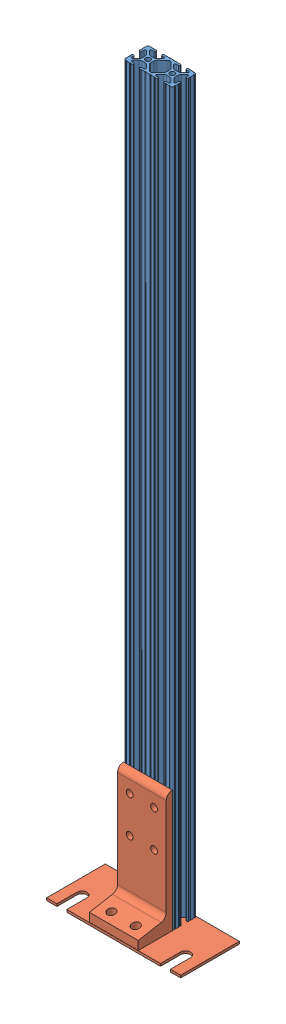
SolidWorks assembly 2010 support assembley, configuration Default. Lengths in mm.
Overall size (139.7 763.52 61.15).
3 component instances, 2 part files, 6 mates.
Components (placement in the parent):
- 8020-1020 29-96in-1: 8020-1020 29-96in [Default] at (16.9292 0 -12.7) x (1 0 0) z (0 -1 0) size (50.8 25.4 760.98)
- 8020-2385-CUT-1: 8020-2385-CUT [Default] at (17.1581 -6.8903 -18.4355) x (0 0 -1) z (1 0 0) (suppressed, hidden)
- 8020-2385-MODIFIED-1: 8020-2385-MODIFIED [Default] at (17.1581 -6.8903 -20.5691) x (0 0 -1) z (1 0 0) size (61.15 129.54 139.7)
Mates (geometry in assembly coordinates):
- Coincident1: coincident anti-aligned: plane of 8020-1020 29-96in-1 through (33.9167 0 -1.049) normal (0 -1 0); plane of assembly through (0 0 0) normal (0 1 0)
- Coincident3: coincident anti-aligned: plane of 8020-1020 29-96in-1 through (33.9167 0 -1.049) normal (0 -1 0); plane of ? through (16.9292 0 142.1782) normal (0 1 0)
- Coincident4: coincident anti-aligned: plane of 8020-1020 29-96in-1 through (14.7956 760.984 -25.4) normal (0 0 -1); plane of ? through (42.3292 -72.7717 -25.4) normal (0 0 1)
- Coincident5: coincident: plane of 8020-1020 29-96in-1 through (19.0628 760.984 0) normal (0 0 1); plane of 8020-2385-MODIFIED-1 through (-8.4708 -72.7717 0) normal (0 0 -1)
- Coincident6: coincident: plane of 8020-1020 29-96in-1 through (33.9167 0 -1.049) normal (0 -1 0); plane of 8020-2385-MODIFIED-1 through (16.9292 0 140.0446) normal (0 1 0)
- Coincident7: coincident: moEndPointRef_w of 8020-1020 29-96in-1; moEndPointRef_w of 8020-2385-MODIFIED-1
